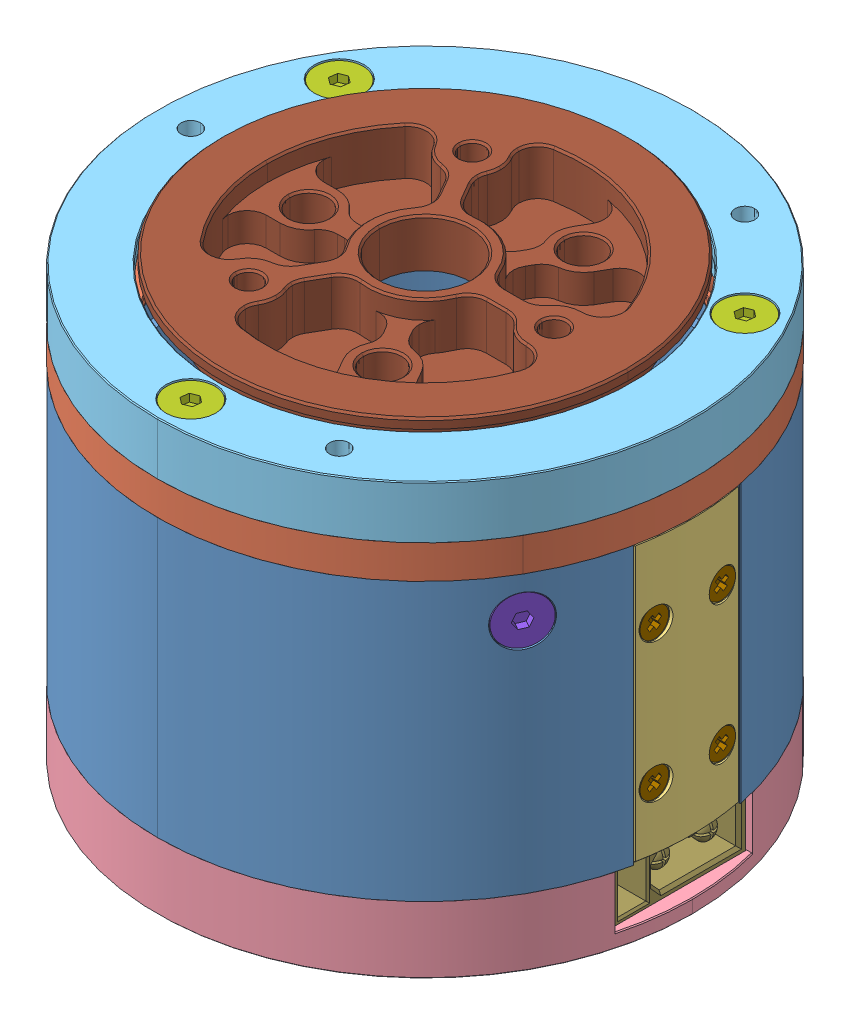
SolidWorks assembly 达秒 4310 减速电机 3D 20221104, configuration 默认. Lengths in mm.
Overall size (76.5 46 76.5).
28 component instances, 12 part files, 0 mates.
Components (placement in the parent):
- 达秒 4310 减速电机 3D 20221104.STEP-1: 达秒 4310 减速电机 3D 20221104.STEP [默认] at origin size (76.5 46 76.5)
  - 4310 ________________3D.STEP-1: 4310 ________________3D.STEP [默认] x (-1 0 0) z (0 0 -1) size (76.5 45 76.5)
    - 4310 ____________3D.STEP-1: 4310 ____________3D.STEP [默认] x (-1 0 0) z (0 0 -1) size (55.43 29.4 56)
    - 4310 __________________B.STEP-1: 4310 __________________B.STEP [默认] at (0 32 0) x (-0.5 0 0.866025) z (0.866025 0 0.5) size (56 3.5 56)
    - 4310 ____________B.STEP-1: 4310 ____________B.STEP [默认] at (0 14.5 0) x (0 0 -1) z (0 1 0) size (11 1.5 28.8)
    - 4310 ________B.STEP-1: 4310 ________B.STEP [默认] at (0 -7 0) x (0 0 -1) z (1 0 0) size (56 7 56)
    - 4310 ________________B.STEP-1: 4310 ________________B.STEP [默认] at (0 38 0) x (-1 0 0) z (0 0 1) size (56 5.9 56)
    - M2.5x10 ______________.STEP-1: M2.5x10 ______________.STEP [默认] at (-17.6777 -6.9 -17.6777) x (-0.608335 0 0.79368) z (-0.79368 0 -0.608335) size (5 10 5)
    - M2.5x8 ______________.STEP-1: M2.5x8 ______________.STEP [默认] at (0 37.9 -24.5) x (0.794624 0 0.607102) z (0.607102 0 -0.794624) size (5 7.7 5)
    - M2.5x8 ______________.STEP-2: M2.5x8 ______________.STEP [默认] at (21.2176 37.9 12.25) x (-0.923078 0 0.384613) z (0.384613 0 0.923078) size (5 7.7 5)
    - M2.5x8 ______________.STEP-3: M2.5x8 ______________.STEP [默认] at (-21.2176 37.9 12.25) x (0.128454 0 -0.991715) z (-0.991715 0 -0.128454) size (5 7.7 5)
    - M2.5x5 ______________.STEP-1: M2.5x5 ______________.STEP [默认] at (-24.1621 24.75 -13.95) x (0.497833 -0.092998 -0.862272) z (-0.046499 -0.995666 0.080538) size (5 5 5)
    - M1.6x3 ______________.STEP-1: M1.6x3 ______________.STEP [默认] at (-27.5 6.5 -3.5) x (0 -0.828384 0.56016) z (0 0.56016 0.828384) size (3 3 3)
    - M1.6x3 ______________.STEP-2: M1.6x3 ______________.STEP [默认] at (-27.5 6.5 3.5) x (0 -0.828384 0.56016) z (0 0.56016 0.828384) size (3 3 3)
    - M1.6x3 ______________.STEP-3: M1.6x3 ______________.STEP [默认] at (-27.5 21 -3.5) x (0 -0.828384 0.56016) z (0 0.56016 0.828384) size (3 3 3)
    - M1.6x3 ______________.STEP-4: M1.6x3 ______________.STEP [默认] at (-27.5 21 3.5) x (0 -0.828384 0.56016) z (0 0.56016 0.828384) size (3 3 3)
    - M2.5x10 ______________.STEP-2: M2.5x10 ______________.STEP [默认] at (17.6777 -6.9 -17.6777) x (-0.79368 0 -0.608335) z (0.608335 0 -0.79368) size (5 10 5)
    - M2.5x10 ______________.STEP-3: M2.5x10 ______________.STEP [默认] at (17.6777 -6.9 17.6777) x (0.608335 0 -0.79368) z (0.79368 0 0.608335) size (5 10 5)
    - M2.5x10 ______________.STEP-4: M2.5x10 ______________.STEP [默认] at (-17.6777 -6.9 17.6777) x (0.79368 0 0.608335) z (-0.608335 0 0.79368) size (5 10 5)
    - M2.5x5 ______________.STEP-2: M2.5x5 ______________.STEP [默认] at (24.1621 24.75 -13.95) x (0.497833 -0.092998 0.862272) z (-0.046499 -0.995666 -0.080538) size (5 5 5)
    - M2.5x5 ______________.STEP-3: M2.5x5 ______________.STEP [默认] at (0 24.75 27.9) x (-0.995666 -0.092998 0) z (0.092998 -0.995666 0) size (5 5 5)
    - M2.5x4 ______________.STEP-1: M2.5x4 ______________.STEP [默认] at (-13.435 -1.65 -13.435) size (4.7 5.61 4.7)
    - M2.5x4 ______________.STEP-2: M2.5x4 ______________.STEP [默认] at (13.435 -1.65 -13.435) x (0 0 1) z (-1 0 0) size (4.7 5.61 4.7)
    - M2.5x4 ______________.STEP-3: M2.5x4 ______________.STEP [默认] at (13.435 -1.65 13.435) x (-1 0 0) z (0 0 -1) size (4.7 5.61 4.7)
    - M2.5x4 ______________.STEP-4: M2.5x4 ______________.STEP [默认] at (-13.435 -1.65 13.435) x (0 0 -1) z (1 0 0) size (4.7 5.61 4.7)
  - 4310 __________________3D.STEP-1: 4310 __________________3D.STEP [默认] at (0 20.9 0) x (0.866025 0 -0.5) z (0.5 0 0.866025) size (58.06 5 58.06)
    - 4310 ______________3D.STEP-1: 4310 ______________3D.STEP [默认] at (0 18.1 0) x (-0.5 0 0.866025) z (0.866025 0 0.5) size (42.5 5 42.5)
  - g43_v1_1_220606a.STEP-1: g43_v1_1_220606a.STEP [默认] at (0 -0.15 0) x (0 0 -1) z (0 -1 0) size (49.13 53.2 8)
